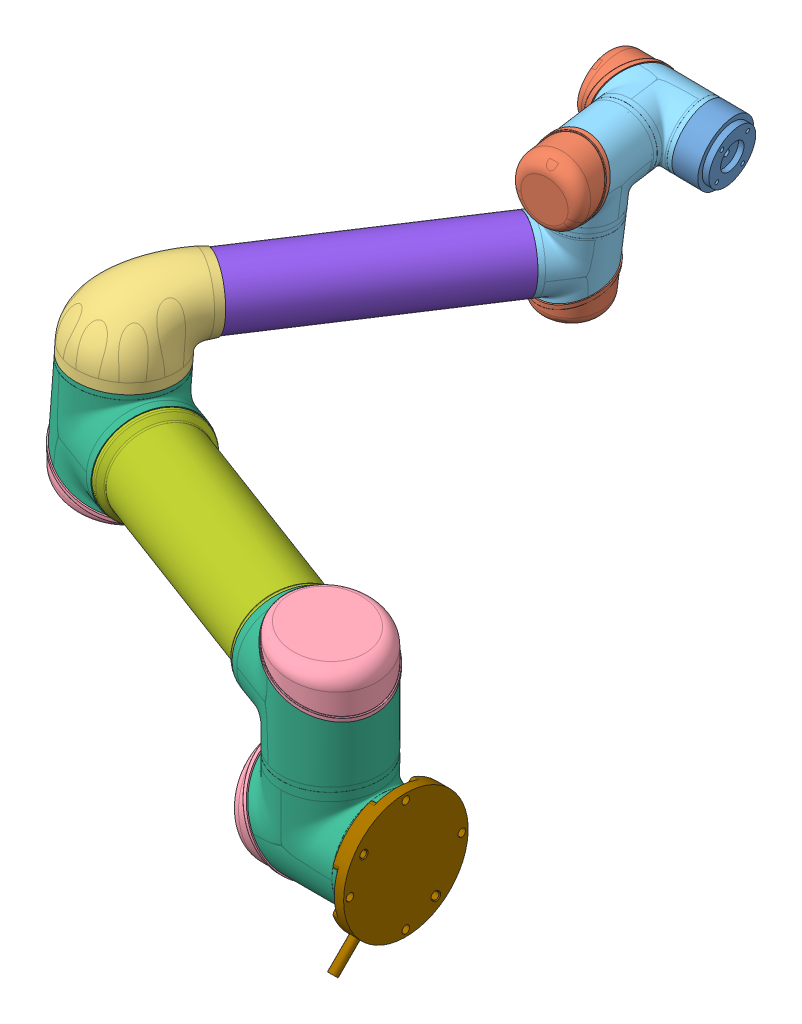
SolidWorks assembly Robot_Simpel_r01, configuration Default. Lengths in mm.
Overall size (565.3 452.97 728.65).
17 component instances, 9 part files, 32 mates.
Components (placement in the parent):
- Size 1_Tool flange_r03_Simple-1: Size 1_Tool flange_r03_Simple [Default] at (-465.4486 -193.8297 -673.0069) x (0.982259 -0.138807 -0.126094) z (0.135926 0.990227 -0.031211) size (34.5 80.5 75)
- Size 1_Joint lid_r07_Simple-1: Size 1_Joint lid_r07_Simple [Default] at (-500.4614 -188.643 -574.76) x (-0.127357 -0.991856 0.000952) z (-0.983922 0.12646 0.126116) size (77.5 51.3 77.52)
- Size 3 to Size 1_Angle_r02_Simple-1: Size 3 to Size 1_Angle_r02_Simple [Default] at (-698.0449 -256.7051 -229.8272) x (-0.473306 0.061618 0.878741) z (-0.880629 -0.008419 -0.473732) size (132.02 97.1 116.06)
- Size 3_Joint lid_r06_Simple-1: Size 3_Joint lid_r06_Simple [Default] at (-302.5995 -511.8734 -73.9327) x (1 0 0) z (0 0 -1) size (62.7 119 119.01)
- Size 3_Joint lid_r06_Simple-2: Size 3_Joint lid_r06_Simple [Default] at (-700.6534 -376.1737 -222.855) x (0.021792 0.998064 -0.058247) z (-0.349727 0.06219 0.934785) size (62.7 119 119.01)
- Size 3_Joint lid_r06_Simple-3: Size 3_Joint lid_r06_Simple [Default] at (-302.5992 -376.1731 -73.9327) x (0 -1 0) z (-0.350405 0 0.936598) size (62.7 119 119.01)
- Size 1_House_r13_Simple-1: Size 1_House_r13_Simple [Default] at (-512.3056 -280.8857 -574.6714) x (-0.473306 0.061618 0.878741) z (0.871643 -0.111463 0.477299) size (83 87.5 75.48)
- Size 3_House_r11_Simple-1: Size 3_House_r11_Simple [Default] at (-302.5992 -376.1734 -73.9327) x (0 -1 0) z (-0.350405 0 0.936598) size (129.79 128.5 124.27)
- Size 3_Over arm_r01_Simpel-1: Size 3_Over arm_r01_Simpel [Default] at (-501.6263 -376.1734 -148.3939) x (0.936598 0 0.350405) z (0.016585 0.998879 -0.044331) size (284 114.3 114.3)
- Size 3_House_r11_Simple-2: Size 3_House_r11_Simple [Default] at (-302.5992 -511.8734 -73.9327) x (1 0 0) z (0 0 -1) size (129.79 128.5 124.27)
- Size 1_Joint lid_r07_Simple-2: Size 1_Joint lid_r07_Simple [Default] at (-512.1059 -187.2364 -667.0174) x (0.125209 -0.015125 0.992015) z (-0.139605 -0.990204 0.002524) size (77.5 51.3 77.52)
- Size 1 rør_r01_Simple-1: Size 1 rør_r01_Simple [Default] at (-604.5245 -268.8801 -403.4576) x (-0.132466 -0.991186 -0.001847) z (0.473306 -0.061618 -0.878741) size (75 75 272.93)
- Size 1_Joint lid_r07_Simple-3: Size 1_Joint lid_r07_Simple [Default] at (-512.3056 -280.8857 -574.6714) x (-0.473306 0.061618 0.878741) z (0.871643 -0.111463 0.477299) size (77.5 51.3 77.52)
- Size 1_House_r13_Simple-2: Size 1_House_r13_Simple [Default] at (-512.1059 -187.2364 -667.0174) x (0.125209 -0.015125 0.992015) z (-0.139605 -0.990204 0.002524) size (83 87.5 75.48)
- Size 3_Round base_r02_Simple-1: Size 3_Round base_r02_Simple [Default] at (-216.3992 -511.8734 -73.9327) size (24 154.92 154.92)
- Size 3_House_r11_Simple-3: Size 3_House_r11_Simple [Default] at (-700.6534 -376.1734 -222.855) x (0.021792 0.998064 -0.058247) z (-0.349727 0.06219 0.934785) size (129.79 128.5 124.27)
- Size 1_House_r13_Simple-3: Size 1_House_r13_Simple [Default] at (-500.4614 -188.643 -574.76) x (-0.127357 -0.991856 0.000952) z (-0.983922 0.12646 0.126116) size (83 87.5 75.48)
Mates (geometry in assembly coordinates):
- 重合2: coincident anti-aligned: plane of Size 1_Tool flange_r03_Simple-1 through (-470.2934 -194.3367 -710.1891) normal (-0.982259 0.138807 0.126094); plane of Size 1_House_r13_Simple-2 through (-465.4486 -193.8297 -673.0069) normal (0.982259 -0.138807 -0.126094)
- 同心1: concentric aligned: cylinder of Size 1_Tool flange_r03_Simple-1 through (-465.4486 -193.8297 -673.0069) axis (-0.982259 0.138807 0.126094) radius 37.5; cylinder of Size 1_House_r13_Simple-2 through (-465.4486 -193.8297 -673.0069) axis (-0.982259 0.138807 0.126094) radius 37.4
- 重合3: coincident anti-aligned: plane of Size 1_Joint lid_r07_Simple-2 through (-569.1528 -335.2916 -619.6977) normal (0.949503 -0.133143 0.284107); plane of Size 1_House_r13_Simple-2 through (-532.0549 -184.4391 -672.9864) normal (-0.949503 0.133143 -0.284107)
- 同心2: concentric aligned: cylinder of Size 1_Joint lid_r07_Simple-2 through (-517.4263 -186.4846 -666.3344) axis (-0.982259 0.138807 0.126094) radius 38.75; cylinder of Size 1_House_r13_Simple-2 through (-460.0137 -194.5978 -673.7046) axis (-0.982259 0.138807 0.126094) radius 37.5
- 重合4: coincident anti-aligned: plane of Size 1_House_r13_Simple-2 through (-506.4089 -187.9246 -621.8807) normal (0.125209 -0.015125 0.992015); plane of Size 1_House_r13_Simple-3 through (-506.4089 -187.9246 -621.8807) normal (-0.125209 0.015125 -0.992015)
- 同心3: concentric anti-aligned: cylinder of Size 1_House_r13_Simple-1 through (-506.2562 -233.7725 -574.7167) axis (-0.127357 -0.991856 0.000952) radius 37.4; cylinder of Size 1_House_r13_Simple-3 through (-506.2562 -233.7725 -574.7167) axis (0.127357 0.991856 -0.000952) radius 37.5
- 重合5: coincident anti-aligned: plane of Size 1_House_r13_Simple-1 through (-510.7499 -300.4811 -582.0886) normal (0.074046 -0.932677 -0.353031); plane of Size 1_Joint lid_r07_Simple-3 through (-402.6486 -336.6505 -463.8587) normal (-0.074046 0.932677 0.353031)
- 同心4: concentric aligned: cylinder of Size 1_House_r13_Simple-1 through (-505.5515 -228.2845 -574.7219) axis (-0.127357 -0.991856 0.000952) radius 37.5; cylinder of Size 1_Joint lid_r07_Simple-3 through (-512.9955 -286.2581 -574.6663) axis (-0.127357 -0.991856 0.000952) radius 38.75
- 重合6: coincident anti-aligned: plane of Size 1_Joint lid_r07_Simple-1 through (-652.8266 -211.4041 -514.0917) normal (-0.165898 -0.385615 -0.907623); plane of Size 1_House_r13_Simple-3 through (-496.9759 -180.5413 -555.6909) normal (0.165898 0.385615 0.907623)
- 同心5: concentric aligned: cylinder of Size 1_Joint lid_r07_Simple-1 through (-499.7832 -188.7249 -569.3867) axis (0.125209 -0.015125 0.992015) radius 38.75; cylinder of Size 1_House_r13_Simple-3 through (-507.1016 -187.8409 -627.3695) axis (0.125209 -0.015125 0.992015) radius 37.5
- 重合7: coincident anti-aligned: plane of Size 1_House_r13_Simple-1 through (-533.841 -278.0821 -534.6887) normal (-0.473306 0.061618 0.878741); plane of Size 1 rør_r01_Simple-1 through (-533.841 -278.0821 -534.6887) normal (0.473306 -0.061618 -0.878741)
- 同心6: concentric anti-aligned: cylinder of Size 1_House_r13_Simple-1 through (-533.841 -278.0821 -534.6887) axis (0.473306 -0.061618 -0.878741) radius 37.5; cylinder of Size 1 rør_r01_Simple-1 through (-534.196 -278.0358 -534.0297) axis (-0.473306 0.061618 0.878741) radius 37.5
- 同心7: concentric anti-aligned: cone of Size 3 to Size 1_Angle_r02_Simple-1 through (-667.7534 -260.6486 -286.0666) axis (0.473306 -0.061618 -0.878741); cylinder of Size 1 rør_r01_Simple-1 through (-534.196 -278.0358 -534.0297) axis (-0.473306 0.061618 0.878741) radius 37.5
- 重合8: coincident anti-aligned: plane of Size 3 to Size 1_Angle_r02_Simple-1 through (-663.0203 -261.2648 -294.854) normal (0.473306 -0.061618 -0.878741); plane of Size 1 rør_r01_Simple-1 through (-695.6784 -256.8669 -312.7526) normal (-0.473306 0.061618 0.878741)
- 重合9: coincident anti-aligned: plane of Size 3 to Size 1_Angle_r02_Simple-1 through (-699.2326 -311.0996 -226.6527) normal (-0.021792 -0.998064 0.058247); plane of Size 3_House_r11_Simple-3 through (-699.2326 -311.0996 -226.6527) normal (0.021792 0.998064 -0.058247)
- 同心8: concentric anti-aligned: cylinder of Size 3 to Size 1_Angle_r02_Simple-1 through (-699.0364 -302.117 -227.177) axis (0.021792 0.998064 -0.058247) radius 58; cylinder of Size 3_House_r11_Simple-3 through (-699.2326 -311.0996 -226.6527) axis (-0.021792 -0.998064 0.058247) radius 57.9
- 重合10: coincident anti-aligned: plane of Size 3_Joint lid_r06_Simple-2 through (-859.7606 -362.1132 15.6475) normal (0.413101 0.905791 0.094291); plane of Size 3_House_r11_Simple-3 through (-713.2543 -403.803 -225.7312) normal (-0.413101 -0.905791 -0.094291)
- 同心9: concentric aligned: cylinder of Size 3_Joint lid_r06_Simple-2 through (-700.7557 -380.8589 -222.5816) axis (-0.021792 -0.998064 0.058247) radius 59.5; cylinder of Size 3_House_r11_Simple-3 through (-696.4979 -185.8505 -233.9623) axis (-0.021792 -0.998064 0.058247) radius 58
- 同心10: concentric anti-aligned: cylinder of Size 3_Over arm_r01_Simpel-1 through (-501.6263 -376.1734 -148.3939) axis (0.936598 0 0.350405) radius 57.15; cylinder of Size 3_House_r11_Simple-3 through (-480.9755 -376.1734 -140.6679) axis (-0.936598 0 -0.350405) radius 58
- 重合11: coincident anti-aligned: plane of Size 3_Over arm_r01_Simpel-1 through (-654.574 -373.4755 -144.8252) normal (-0.936598 0 -0.350405); plane of Size 3_House_r11_Simple-3 through (-634.6232 -376.1734 -198.1515) normal (0.936598 0 0.350405)
- 重合12: coincident anti-aligned: plane of Size 3_House_r11_Simple-1 through (-368.6294 -376.1734 -98.6363) normal (-0.936598 0 -0.350405); plane of Size 3_Over arm_r01_Simpel-1 through (-388.5801 -373.4755 -45.3101) normal (0.936598 0 0.350405)
- 重合13: coincident anti-aligned: plane of Size 3_Joint lid_r06_Simple-3 through (-339.2285 -372.847 210.7486) normal (-0.393324 -0.907547 -0.147153); plane of Size 3_House_r11_Simple-1 through (-290.6015 -348.4902 -69.4441) normal (0.393324 0.907547 0.147153)
- 同心11: concentric aligned: cylinder of Size 3_Joint lid_r06_Simple-3 through (-302.5992 -371.4787 -73.9327) axis (0 1 0) radius 59.5; cylinder of Size 3_House_r11_Simple-1 through (-302.5992 -566.8653 -73.9327) axis (0 1 0) radius 58
- 同心12: concentric anti-aligned: cylinder of Size 3_House_r11_Simple-1 through (-302.5992 -441.3734 -73.9327) axis (0 1 0) radius 57.9; cylinder of Size 3_House_r11_Simple-2 through (-302.5992 -277.3246 -73.9327) axis (0 -1 0) radius 58
- 同心13: concentric aligned: cylinder of Size 3_House_r11_Simple-1 through (-522.2771 -376.1734 -156.1199) axis (0.936598 0 0.350405) radius 58; cylinder of Size 3_Over arm_r01_Simpel-1 through (-501.6263 -376.1734 -148.3939) axis (0.936598 0 0.350405) radius 57.15
- 重合14: coincident anti-aligned: plane of Size 3_House_r11_Simple-1 through (-302.5992 -441.3734 -73.9327) normal (0 -1 0); plane of Size 3_House_r11_Simple-2 through (-302.5992 -441.3734 -73.9327) normal (0 1 0)
- 重合15: coincident anti-aligned: plane of Size 3_Joint lid_r06_Simple-1 through (-305.9256 -577.3203 -353.3999) normal (0.907547 0.41995 0); plane of Size 3_House_r11_Simple-2 through (-330.2824 -524.6832 -73.9327) normal (-0.907547 -0.41995 0)
- 同心14: concentric aligned: cylinder of Size 3_Joint lid_r06_Simple-1 through (-307.2938 -511.8734 -73.9327) axis (-1 0 0) radius 59.5; cylinder of Size 3_House_r11_Simple-2 through (-111.9072 -511.8734 -73.9327) axis (-1 0 0) radius 58
- 重合16: coincident anti-aligned: plane of Size 3_House_r11_Simple-2 through (-237.3992 -511.8734 -73.9327) normal (1 0 0); plane of Size 3_Round base_r02_Simple-1 through (-237.3992 -455.7734 -73.9327) normal (-1 0 0)
- 同心15: concentric aligned: cylinder of Size 3_House_r11_Simple-2 through (-237.3992 -511.8734 -73.9327) axis (-1 0 0) radius 57.9; cylinder of Size 3_Round base_r02_Simple-1 through (-213.3992 -511.8734 -73.9327) axis (-1 0 0) radius 73.5
- 同心16: concentric anti-aligned: cylinder of Size 1_House_r13_Simple-2 through (-506.4089 -187.9246 -621.8807) axis (-0.125209 0.015125 -0.992015) radius 37.5; cylinder of Size 1_House_r13_Simple-3 through (-506.4089 -187.9246 -621.8807) axis (0.125209 -0.015125 0.992015) radius 37.4
- 重合17: coincident anti-aligned: plane of Size 1_House_r13_Simple-1 through (-506.2562 -233.7725 -574.7167) normal (0.127357 0.991856 -0.000952); plane of Size 1_House_r13_Simple-3 through (-506.2562 -233.7725 -574.7167) normal (-0.127357 -0.991856 0.000952)
